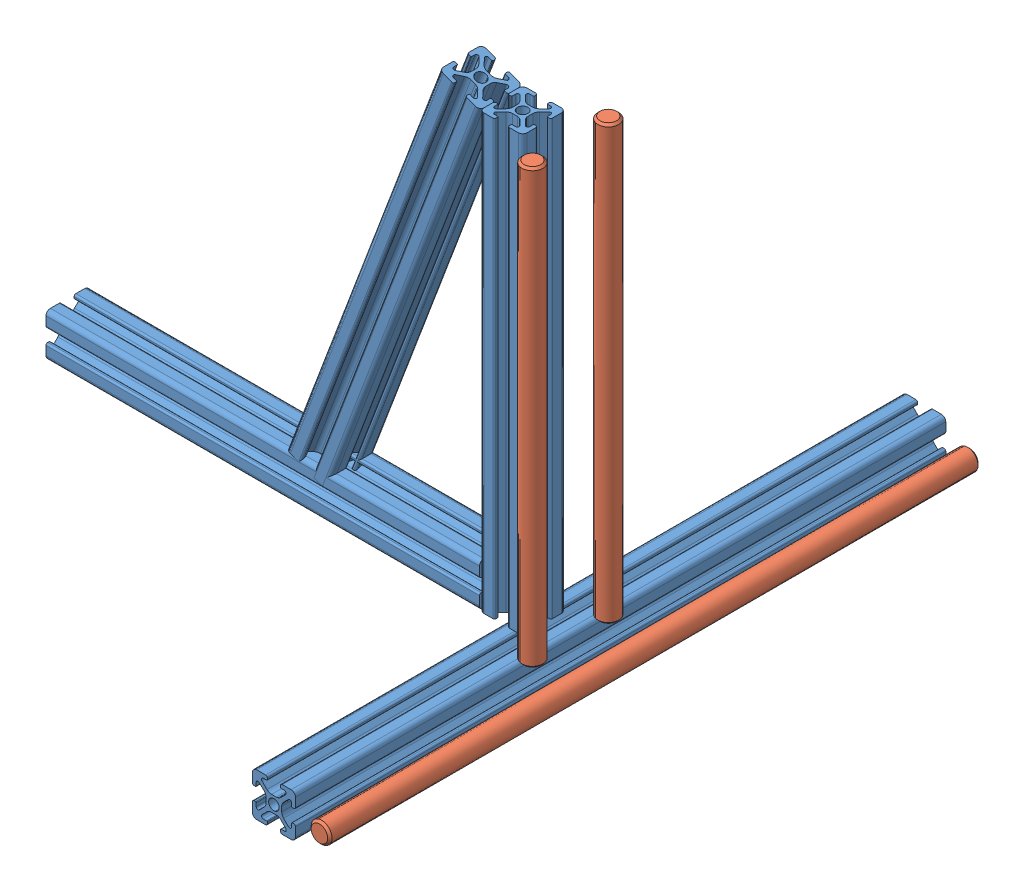
SolidWorks assembly Robot, configuration Default. Lengths in mm.
Overall size (237.11 236.97 301).
10 component instances, 5 part files, 24 mates.
Components (placement in the parent):
- AluminumExtrusion-1: AluminumExtrusion [Default] at (-17.3532 7.9503 2.5368) size (20.16 19.9 300)
- ThreeEighthsRod-1: ThreeEighthsRod [Default] at (4.6468 7.9503 3.5368) x (0.999018 0.044311 0) z (0 0 1) size (9.65 9.65 300)
- AluminumExtrusion-2: AluminumExtrusion [Shorter] at (-17.3532 127.9503 37.7686) x (1 0 0) z (0 -1 0) size (19.9 19.9 200)
- ThreeEighthsRod-2: ThreeEighthsRod [Shorter] at (4.6468 127.9503 55.2686) x (0.997391 0 -0.072189) z (0 -1 0) size (9.65 9.65 200)
- ThreeEighthsRod-3: ThreeEighthsRod [Shorter] at (4.6468 127.9503 20.2686) x (1 0 0) z (0 -1 0) size (9.65 9.65 200)
- Part3^Robot-1: Part3^Robot [Default] at (-17.3532 227.9503 37.7686) x (-1 0 0) z (0 1 0) size (24.5 35 0) (virtual)
- Part4^Robot-1: Part4^Robot [Default] at (-17.3532 7.9503 152.5368) size (24.5 5 0) (virtual)
- Part5^Robot-1: Part5^Robot [Default] at (4.6468 7.9503 37.7686) x (-1 0 0) z (0 1 0) size (24.5 20 20) (virtual)
- AluminumExtrusion-3: AluminumExtrusion [Shorter] at (-71.9126 137.9003 37.7686) x (0.935623 -0.353 0) z (-0.353 -0.935623 0) size (19.9 19.9 200)
- AluminumExtrusion-4: AluminumExtrusion [Shorter] at (-127.3032 37.9003 37.7686) x (0 -1 0) z (-1 0 0) size (19.9 19.9 200)
Mates (geometry in assembly coordinates):
- Coincident3: coincident aligned: plane of AluminumExtrusion-2 through (-18.4417 27.9503 44.3488) normal (0 -1 0); plane of ThreeEighthsRod-2 through (4.6468 27.9503 55.2686) normal (0 -1 0)
- Concentric1: concentric anti-aligned: circle of AluminumExtrusion-2; circle of Part3^Robot-1
- Coincident10: coincident aligned: plane of AluminumExtrusion-2 through (-18.4417 227.9503 44.3488) normal (0 1 0); circle of Part3^Robot-1
- Parallel2: parallel: plane of AluminumExtrusion-2 through (-25.2966 27.9503 47.7186) normal (0 0 1); line of Part3^Robot-1 through (-17.3532 227.9503 37.7686) axis (1 0 0)
- Coincident12: coincident: point of ThreeEighthsRod-3; point of Part3^Robot-1
- Coincident13: coincident: point of ThreeEighthsRod-2; point of Part3^Robot-1
- Concentric2: concentric aligned: circle of AluminumExtrusion-1; circle of Part4^Robot-1
- Coincident14: coincident aligned: plane of AluminumExtrusion-1 through (-18.4417 14.5305 152.5368) normal (0 0 1); circle of Part4^Robot-1
- Parallel3: parallel: plane of AluminumExtrusion-1 through (-9.4098 17.9003 152.5368) normal (0 1 0); line of Part4^Robot-1 through (-17.3532 7.9503 152.5368) axis (1 0 0)
- Coincident16: coincident: point of ThreeEighthsRod-1; point of Part4^Robot-1
- Concentric3: concentric anti-aligned: circle of AluminumExtrusion-2; circle of Part5^Robot-1
- Coincident18: coincident anti-aligned: plane of AluminumExtrusion-2 through (-18.4417 27.9503 44.3488) normal (0 -1 0); circle of Part5^Robot-1
- Parallel4: parallel: plane of AluminumExtrusion-2 through (-9.4098 27.9503 47.7186) normal (0 0 1); line of Part5^Robot-1 through (4.6468 27.9503 37.7686) axis (-1 0 0)
- Coincident20: coincident anti-aligned: line of ThreeEighthsRod-1 through (4.6468 7.9503 -146.4632) axis (0 0 1); line of Part5^Robot-1 through (4.6468 7.9503 47.7686) axis (0 0 -1)
- Parallel5: parallel anti-aligned: line of AluminumExtrusion-1 through (-7.4032 15.8937 152.5368) axis (0 0 -1); line of ThreeEighthsRod-1 through (4.6468 7.9503 -146.4632) axis (0 0 1)
- Parallel6: parallel anti-aligned: line of AluminumExtrusion-2 through (-9.4098 27.9503 47.7186) axis (0 1 0); line of ThreeEighthsRod-2 through (4.6468 227.9503 55.2686) axis (0 -1 0)
- Parallel7: parallel anti-aligned: line of AluminumExtrusion-2 through (-7.4032 27.9503 29.8252) axis (0 1 0); line of ThreeEighthsRod-3 through (4.6468 227.9503 20.2686) axis (0 -1 0)
- Parallel8: parallel anti-aligned: plane of AluminumExtrusion-1 through (-9.4098 17.9003 152.5368) normal (0 1 0); plane of AluminumExtrusion-2 through (-18.4417 27.9503 44.3488) normal (0 -1 0)
- Coincident26: coincident anti-aligned: plane of AluminumExtrusion-2 through (-27.3032 27.9503 45.712) normal (-1 0 0); plane of AluminumExtrusion-4 through (-27.3032 38.9888 44.3488) normal (1 0 0)
- Coincident27: coincident aligned: plane of AluminumExtrusion-2 through (-25.2966 27.9503 47.7186) normal (0 0 1); plane of AluminumExtrusion-4 through (-227.3032 29.9569 47.7186) normal (0 0 1)
- Coincident28: coincident aligned: plane of AluminumExtrusion-2 through (-18.4417 27.9503 44.3488) normal (0 -1 0); plane of AluminumExtrusion-4 through (-227.3032 27.9503 45.712) normal (0 -1 0)
- Coincident29: coincident aligned: plane of AluminumExtrusion-3 through (-117.3727 48.4854 47.7186) normal (0 0 1); plane of AluminumExtrusion-4 through (-227.3032 45.8437 47.7186) normal (0 0 1)
- Coincident31: coincident anti-aligned: line of AluminumExtrusion-2 through (-27.3032 227.9503 45.712) axis (0 0 -1); line of AluminumExtrusion-3 through (-27.3032 227.9503 41.596) axis (0 0 1)
- Coincident32: coincident: point of AluminumExtrusion-3; line of AluminumExtrusion-4 through (-227.3032 47.8503 45.712) axis (1 0 0)
